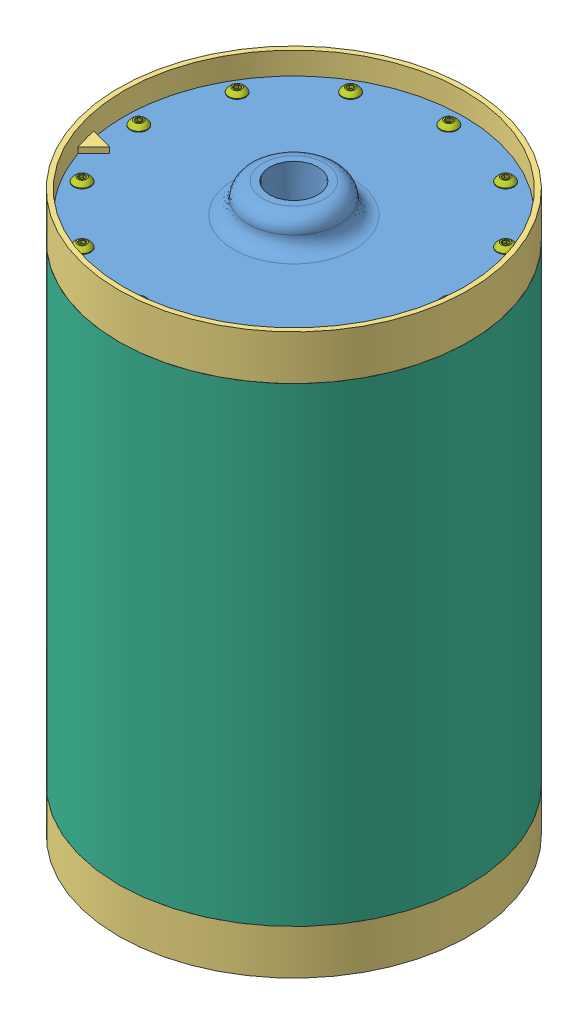
SolidWorks assembly Cryo Tank, configuration Default. Lengths in mm.
Overall size (99.44 162.69 99.44).
33 component instances, 8 part files, 26 mates.
Components (placement in the parent):
- 0301-C; End Cap-1: 0301-C; End Cap [Default] at origin size (96.52 28.96 96.52)
- Liner-1: Liner [Default] at (0 -4.7625 0) size (79.38 133.35 79.38)
- 0201-C; Main Ring-1: 0201-C; Main Ring [Default] at (0 -1.5875 0) size (99.34 25.4 99.34)
- 0201-C; Main Ring-2: 0201-C; Main Ring [Default] at (0 -141.2875 0) x (-1 0 0) z (0 0 1) size (99.34 25.4 99.34)
- 0301-C; End Cap-2: 0301-C; End Cap [Default] at (0 -142.875 0) x (-1 0 0) z (0 0 1) size (96.52 28.96 96.52)
- CF Inner Layer-1: CF Inner Layer [Default] at (0 64.2407 0) size (86.23 133.35 86.23)
- Honeycomb Core-1: Honeycomb Core [Default] at (0 -50.3801 0) size (98.93 133.35 98.93)
- CF Outer Layer-1: CF Outer Layer [Default] at (0 15.1434 0) size (99.44 133.35 99.44)
- 92949A325_18-8 SS BUTTON-HEAD SOCKET CAP SCREW-1: 92949A325_18-8 SS BUTTON-HEAD SOCKET CAP SCREW [92949A325] at (43.9737 2.9083 0) x (1 0 0) z (0 1 0) size (4.78 4.78 7.95)
- 92949A325_18-8 SS BUTTON-HEAD SOCKET CAP SCREW-2: 92949A325_18-8 SS BUTTON-HEAD SOCKET CAP SCREW [92949A325] at (43.9737 -145.7833 0) x (1 0 0) z (0 -1 0) size (4.78 4.78 7.95)
- 92949A325_18-8 SS BUTTON-HEAD SOCKET CAP SCREW-3: 92949A325_18-8 SS BUTTON-HEAD SOCKET CAP SCREW [92949A325] at (38.0824 -145.7833 -21.9869) x (0.866025 0 -0.5) z (0 -1 0) size (4.78 4.78 7.95)
- 92949A325_18-8 SS BUTTON-HEAD SOCKET CAP SCREW-4: 92949A325_18-8 SS BUTTON-HEAD SOCKET CAP SCREW [92949A325] at (21.9869 -145.7833 -38.0824) x (0.5 0 -0.866025) z (0 -1 0) size (4.78 4.78 7.95)
- 92949A325_18-8 SS BUTTON-HEAD SOCKET CAP SCREW-5: 92949A325_18-8 SS BUTTON-HEAD SOCKET CAP SCREW [92949A325] at (0 -145.7833 -43.9737) x (0 0 -1) z (0 -1 0) size (4.78 4.78 7.95)
- 92949A325_18-8 SS BUTTON-HEAD SOCKET CAP SCREW-6: 92949A325_18-8 SS BUTTON-HEAD SOCKET CAP SCREW [92949A325] at (-21.9869 -145.7833 -38.0824) x (-0.5 0 -0.866025) z (0 -1 0) size (4.78 4.78 7.95)
- 92949A325_18-8 SS BUTTON-HEAD SOCKET CAP SCREW-7: 92949A325_18-8 SS BUTTON-HEAD SOCKET CAP SCREW [92949A325] at (-38.0824 -145.7833 -21.9869) x (-0.866025 0 -0.5) z (0 -1 0) size (4.78 4.78 7.95)
- 92949A325_18-8 SS BUTTON-HEAD SOCKET CAP SCREW-8: 92949A325_18-8 SS BUTTON-HEAD SOCKET CAP SCREW [92949A325] at (-43.9737 -145.7833 0) x (-1 0 0) z (0 -1 0) size (4.78 4.78 7.95)
- 92949A325_18-8 SS BUTTON-HEAD SOCKET CAP SCREW-9: 92949A325_18-8 SS BUTTON-HEAD SOCKET CAP SCREW [92949A325] at (-38.0824 -145.7833 21.9869) x (-0.866025 0 0.5) z (0 -1 0) size (4.78 4.78 7.95)
- 92949A325_18-8 SS BUTTON-HEAD SOCKET CAP SCREW-10: 92949A325_18-8 SS BUTTON-HEAD SOCKET CAP SCREW [92949A325] at (-21.9869 -145.7833 38.0824) x (-0.5 0 0.866025) z (0 -1 0) size (4.78 4.78 7.95)
- 92949A325_18-8 SS BUTTON-HEAD SOCKET CAP SCREW-11: 92949A325_18-8 SS BUTTON-HEAD SOCKET CAP SCREW [92949A325] at (0 -145.7833 43.9737) x (0 0 1) z (0 -1 0) size (4.78 4.78 7.95)
- 92949A325_18-8 SS BUTTON-HEAD SOCKET CAP SCREW-12: 92949A325_18-8 SS BUTTON-HEAD SOCKET CAP SCREW [92949A325] at (21.9869 -145.7833 38.0824) x (0.5 0 0.866025) z (0 -1 0) size (4.78 4.78 7.95)
- 92949A325_18-8 SS BUTTON-HEAD SOCKET CAP SCREW-13: 92949A325_18-8 SS BUTTON-HEAD SOCKET CAP SCREW [92949A325] at (38.0824 -145.7833 21.9869) x (0.866025 0 0.5) z (0 -1 0) size (4.78 4.78 7.95)
- 92949A325_18-8 SS BUTTON-HEAD SOCKET CAP SCREW-14: 92949A325_18-8 SS BUTTON-HEAD SOCKET CAP SCREW [92949A325] at (38.0824 2.9083 -21.9869) x (0.866025 0 -0.5) z (0 1 0) size (4.78 4.78 7.95)
- 92949A325_18-8 SS BUTTON-HEAD SOCKET CAP SCREW-15: 92949A325_18-8 SS BUTTON-HEAD SOCKET CAP SCREW [92949A325] at (21.9869 2.9083 -38.0824) x (0.5 0 -0.866025) z (0 1 0) size (4.78 4.78 7.95)
- 92949A325_18-8 SS BUTTON-HEAD SOCKET CAP SCREW-16: 92949A325_18-8 SS BUTTON-HEAD SOCKET CAP SCREW [92949A325] at (0 2.9083 -43.9737) x (0 0 -1) z (0 1 0) size (4.78 4.78 7.95)
- 92949A325_18-8 SS BUTTON-HEAD SOCKET CAP SCREW-17: 92949A325_18-8 SS BUTTON-HEAD SOCKET CAP SCREW [92949A325] at (-21.9869 2.9083 -38.0824) x (-0.5 0 -0.866025) z (0 1 0) size (4.78 4.78 7.95)
- 92949A325_18-8 SS BUTTON-HEAD SOCKET CAP SCREW-18: 92949A325_18-8 SS BUTTON-HEAD SOCKET CAP SCREW [92949A325] at (-38.0824 2.9083 -21.9869) x (-0.866025 0 -0.5) z (0 1 0) size (4.78 4.78 7.95)
- 92949A325_18-8 SS BUTTON-HEAD SOCKET CAP SCREW-19: 92949A325_18-8 SS BUTTON-HEAD SOCKET CAP SCREW [92949A325] at (-43.9737 2.9083 0) x (-1 0 0) z (0 1 0) size (4.78 4.78 7.95)
- 92949A325_18-8 SS BUTTON-HEAD SOCKET CAP SCREW-20: 92949A325_18-8 SS BUTTON-HEAD SOCKET CAP SCREW [92949A325] at (-38.0824 2.9083 21.9869) x (-0.866025 0 0.5) z (0 1 0) size (4.78 4.78 7.95)
- 92949A325_18-8 SS BUTTON-HEAD SOCKET CAP SCREW-21: 92949A325_18-8 SS BUTTON-HEAD SOCKET CAP SCREW [92949A325] at (-21.9869 2.9083 38.0824) x (-0.5 0 0.866025) z (0 1 0) size (4.78 4.78 7.95)
- 92949A325_18-8 SS BUTTON-HEAD SOCKET CAP SCREW-22: 92949A325_18-8 SS BUTTON-HEAD SOCKET CAP SCREW [92949A325] at (0 2.9083 43.9737) x (0 0 1) z (0 1 0) size (4.78 4.78 7.95)
- 92949A325_18-8 SS BUTTON-HEAD SOCKET CAP SCREW-23: 92949A325_18-8 SS BUTTON-HEAD SOCKET CAP SCREW [92949A325] at (21.9869 2.9083 38.0824) x (0.5 0 0.866025) z (0 1 0) size (4.78 4.78 7.95)
- 92949A325_18-8 SS BUTTON-HEAD SOCKET CAP SCREW-24: 92949A325_18-8 SS BUTTON-HEAD SOCKET CAP SCREW [92949A325] at (38.0824 2.9083 21.9869) x (0.866025 0 0.5) z (0 1 0) size (4.78 4.78 7.95)
- Inner Honeycomb Layer-1: Inner Honeycomb Layer [Default] at (0 -54.4416 0) size (85.72 107.95 85.72)
Mates (geometry in assembly coordinates):
- Coincident13: coincident: point of Liner-1; point of assembly
- Coincident14: coincident aligned: plane of Liner-1 through (0 -4.7625 0) normal (0 0 1); plane of assembly through (0 0 0) normal (0 0 1)
- Coincident15: coincident aligned: plane of 0301-C; End Cap-1 through (0 0 0) normal (0 0 1); plane of assembly through (0 0 0) normal (0 0 1)
- Coincident16: coordinate: point of 0301-C; End Cap-1; point of assembly
- Coincident20: coincident anti-aligned: line of 0201-C; Main Ring-1 through (110 0 53.4125) axis (0 0 -1); line of assembly
- Coincident21: coincident aligned: plane of 0201-C; Main Ring-1 through (0 -1.5875 0) normal (0 0 1); plane of assembly through (0 0 0) normal (0 0 1)
- Coincident22: coincident: point of 0201-C; Main Ring-1; point of assembly
- Coincident26: coincident aligned: line of 0301-C; End Cap-2 through (110 0 -197.875) axis (0 0 1); line of assembly
- Coincident27: coincident aligned: plane of 0301-C; End Cap-2 through (0 -142.875 0) normal (0 0 1); plane of assembly through (0 0 0) normal (0 0 1)
- Coincident28: coincident: point of 0301-C; End Cap-2; point of assembly
- Coincident29: coincident aligned: line of 0201-C; Main Ring-2 through (110 0 -196.2875) axis (0 0 1); line of assembly
- Coincident30: coincident aligned: plane of 0201-C; Main Ring-2 through (0 -141.2875 0) normal (0 0 1); plane of assembly through (0 0 0) normal (0 0 1)
- Coincident31: coincident: point of 0201-C; Main Ring-2; point of assembly
- Coincident35: coincident aligned: line of 0201-C; Main Ring-1 through (110 0 53.4125) axis (0 0 -1); line of CF Inner Layer-1 through (110 0 119.2407) axis (0 0 -1)
- Coincident36: coincident aligned: plane of CF Inner Layer-1 through (0 64.2407 0) normal (0 0 1); plane of assembly through (0 0 0) normal (0 0 1)
- Coincident37: coincident aligned: line of CF Inner Layer-1 through (110 0 119.2407) axis (0 0 -1); line of Honeycomb Core-1 through (110 0 4.6199) axis (0 0 -1)
- Coincident38: coincident aligned: plane of Honeycomb Core-1 through (0 -50.3801 0) normal (0 0 1); plane of assembly through (0 0 0) normal (0 0 1)
- Coincident39: coincident aligned: line of CF Inner Layer-1 through (110 0 119.2407) axis (0 0 -1); line of CF Outer Layer-1 through (110 0 70.1434) axis (0 0 -1)
- Coincident40: coincident aligned: plane of CF Outer Layer-1 through (0 15.1434 0) normal (0 0 1); plane of assembly through (0 0 0) normal (0 0 1)
- Coincident44: coincident anti-aligned: line of Inner Honeycomb Layer-1 through (110 0 0.5584) axis (0 0 -1); line of assembly
- Coincident45: coincident anti-aligned: plane of 0301-C; End Cap-1 through (-48.26 1.5875 0) normal (0 1 0); plane of 92949A325_18-8 SS BUTTON-HEAD SOCKET CAP SCREW-19 through (-43.9737 1.5875 -2.3876) normal (0 -1 0)
- Concentric1: concentric: point of 0301-C; End Cap-1; cylinder of 92949A325_18-8 SS BUTTON-HEAD SOCKET CAP SCREW-19 through (-43.9737 2.9083 0) axis (0 1 0) radius 2.3876
- Coincident47: coincident anti-aligned: plane of 92949A325_18-8 SS BUTTON-HEAD SOCKET CAP SCREW-1 through (43.9737 2.9083 0) normal (0 0 -1); plane of assembly through (0 0 0) normal (0 0 1)
- Coincident48: coincident anti-aligned: plane of 0301-C; End Cap-2 through (48.26 -144.4625 0) normal (0 -1 0); plane of 92949A325_18-8 SS BUTTON-HEAD SOCKET CAP SCREW-8 through (-43.9737 -144.4625 2.3876) normal (0 1 0)
- Concentric2: concentric aligned: cylinder of 0301-C; End Cap-2 through (-43.9737 -144.4625 0) axis (0 -1 0) radius 1.3526; cylinder of 92949A325_18-8 SS BUTTON-HEAD SOCKET CAP SCREW-8 through (-43.9737 -145.7833 0) axis (0 -1 0) radius 2.3876
- Coincident49: coincident aligned: plane of 92949A325_18-8 SS BUTTON-HEAD SOCKET CAP SCREW-2 through (43.9737 -145.7833 0) normal (0 0 1); plane of assembly through (0 0 0) normal (0 0 1)
